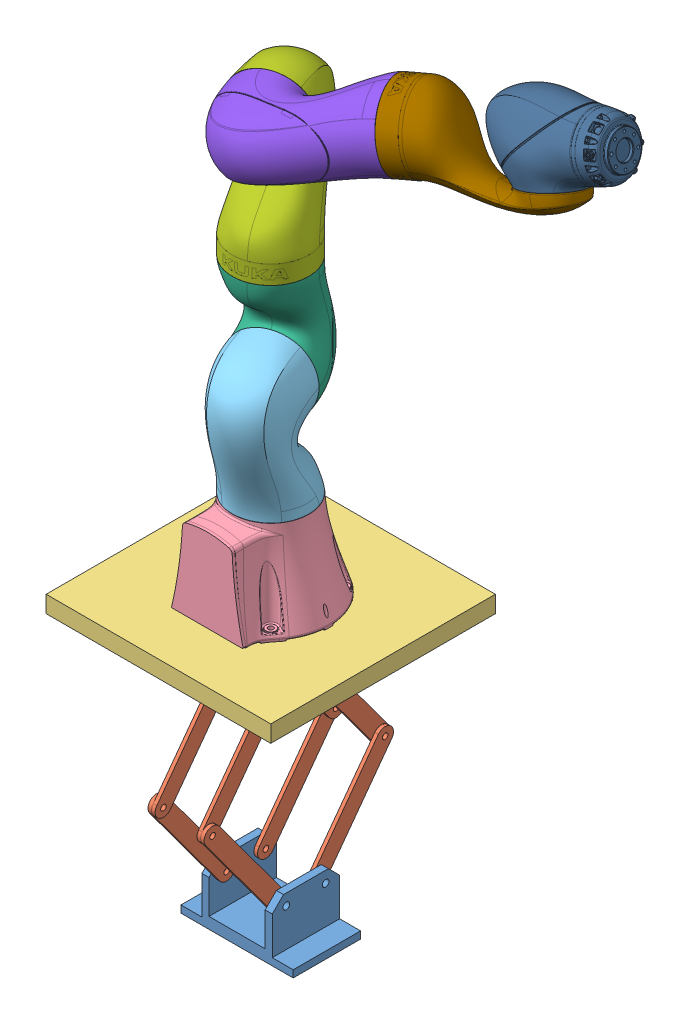
SolidWorks assembly Montagem_Base_1DOF, configuration Valor predeterminado. Lengths in mm.
Overall size (709.5 1448.5 430.81).
20 component instances, 10 part files, 6 mates.
Components (placement in the parent):
- Motagem_Macaco-1: Motagem_Macaco [Valor predeterminado] at origin size (200 481.91 349.38)
  - Base_Macaco-1: Base_Macaco [Valor predeterminado] at origin size (200 100 120)
  - Haste_Macaco-1: Haste_Macaco [Valor predeterminado] at (43.65 80 35) x (0 0.593574 -0.804779) z (1 0 0) size (30 230 6.35)
  - Haste_Macaco-2: Haste_Macaco [Valor predeterminado] at (-43.65 80 35) x (0 -0.593574 0.804779) z (-1 0 0) size (30 230 6.35)
  - Haste_Macaco-3: Haste_Macaco [Valor predeterminado] at (43.65 80 -35) x (0 -0.593574 -0.804779) z (1 0 0) size (30 230 6.35)
  - Haste_Macaco-4: Haste_Macaco [Valor predeterminado] at (-43.65 80 -35) x (0 0.593574 0.804779) z (-1 0 0) size (30 230 6.35)
  - Haste_Macaco-5: Haste_Macaco [Valor predeterminado] at (43.65 240.9559 153.7148) x (0 0.593574 0.804779) z (-1 0 0) size (30 230 6.35)
  - Haste_Macaco-6: Haste_Macaco [Valor predeterminado] at (43.65 240.9559 -153.7148) x (0 -0.593574 0.804779) z (-1 0 0) size (30 230 6.35)
  - Haste_Macaco-7: Haste_Macaco [Valor predeterminado] at (-43.65 240.9559 -153.7148) x (0 0.593574 -0.804779) z (1 0 0) size (30 230 6.35)
  - Haste_Macaco-9: Haste_Macaco [Valor predeterminado] at (-43.65 240.9559 153.7148) x (0 -0.593574 -0.804779) z (1 0 0) size (30 230 6.35)
  - Base_Macaco-3: Base_Macaco [Valor predeterminado] at (0 481.9118 0) x (-1 0 0) z (0 0 1) size (200 100 120)
- Base_Robo-1: Base_Robo [KUKA LBR IIWA] at (0 481.9118 0) size (400 92.5 400)
- LBR IIWA7 R800-1: LBR IIWA7 R800 [Valor predeterminado] at (-0.0002 511.9118 0.0002) x (0 0 1) z (-1 0 0) size (367.78 937.05 614.91) (flexible)
  - Salvar corpos1[3]-1: Salvar corpos1[3] [Valor predeterminado] x (-1 0 0) z (0 1 0) size (216.97 207.92 158.45)
  - Salvar corpos1[5]-1: Salvar corpos1[5] [Valor predeterminado] at (0 0.5 0) x (-0.323637 0 -0.946181) z (0 1 0) size (136.04 183.92 262.67)
  - Salvar corpos1[7]-1: Salvar corpos1[7] [Valor predeterminado] at (0.4731 0.5 -0.1618) x (-0.323637 0 -0.946181) z (0 1 0) size (143.98 187.74 257.82)
  - Salvar corpos1[2]-1: Salvar corpos1[2] [Valor predeterminado] at (0.4731 0 -0.1618) x (-0.338048 0 -0.941129) z (0 1 0) size (138.59 185.21 295.17)
  - Salvar corpos1[8]-1: Salvar corpos1[8] [Valor predeterminado] at (244.8299 588.0806 681.6083) x (-0.0694 -0.9787 -0.19321) z (-0.330848 0.205296 -0.921083) size (143.98 187.74 257.82)
  - Salvar corpos1[1]-1: Salvar corpos1[1] [Valor predeterminado] at (244.9953 587.978 682.0689) x (-0.909184 -0.330848 0.252832) z (-0.330848 0.205296 -0.921083) size (136.35 187.82 284.12)
  - Salvar corpos1[9]-3: Salvar corpos1[9] [Valor predeterminado] at (-33.3692 498.4009 720.6632) x (-0.963634 -0.267103 0.008056) z (-0.086513 0.283307 -0.955119) size (132.93 138.22 212.19)
Mates (geometry in assembly coordinates):
- Largura1: width anti-aligned: plane of Base_Robo-1 through (-200 511.9118 200) normal (-1 0 0); plane of Base_Robo-1 through (200 511.9118 200) normal (1 0 0); plane of Motagem_Macaco-1/Base_Macaco-3 through (100 481.9118 60) normal (1 0 0); plane of Motagem_Macaco-1/Base_Macaco-3 through (-100 481.9118 60) normal (-1 0 0)
- Largura2: width anti-aligned: plane of Base_Robo-1 through (-200 511.9118 200) normal (0 0 1); plane of Base_Robo-1 through (-200 511.9118 -200) normal (0 0 -1); plane of Motagem_Macaco-1/Base_Macaco-3 through (0 481.9118 -60) normal (0 0 -1); plane of Motagem_Macaco-1/Base_Macaco-3 through (0 481.9118 60) normal (0 0 1)
- Coincidente1: coincident anti-aligned: plane of Motagem_Macaco-1/Base_Macaco-3 through (100 481.9118 60) normal (0 1 0); plane of Base_Robo-1 through (0 481.9118 0) normal (0 -1 0)
- Coincidente2: coincident anti-aligned: plane of Base_Robo-1 through (0 511.9118 0) normal (0 1 0); plane of LBR IIWA7 R800-1/Salvar corpos1[3]-1 through (-0.0002 511.9118 0.0002) normal (0 -1 0)
- Concêntrico1: concentric anti-aligned: cylinder of Base_Robo-1 through (-65.054 419.4118 65.054) axis (0 1 0) radius 8; cylinder of LBR IIWA7 R800-1/Salvar corpos1[3]-1 through (-65.054 561.9118 65.054) axis (0 -1 0) radius 4.5
- Coincidente3: coincident anti-aligned: plane of LBR IIWA7 R800-1/Salvar corpos1[3]-1; plane of assembly through (0 0 0) normal (1 0 0)
